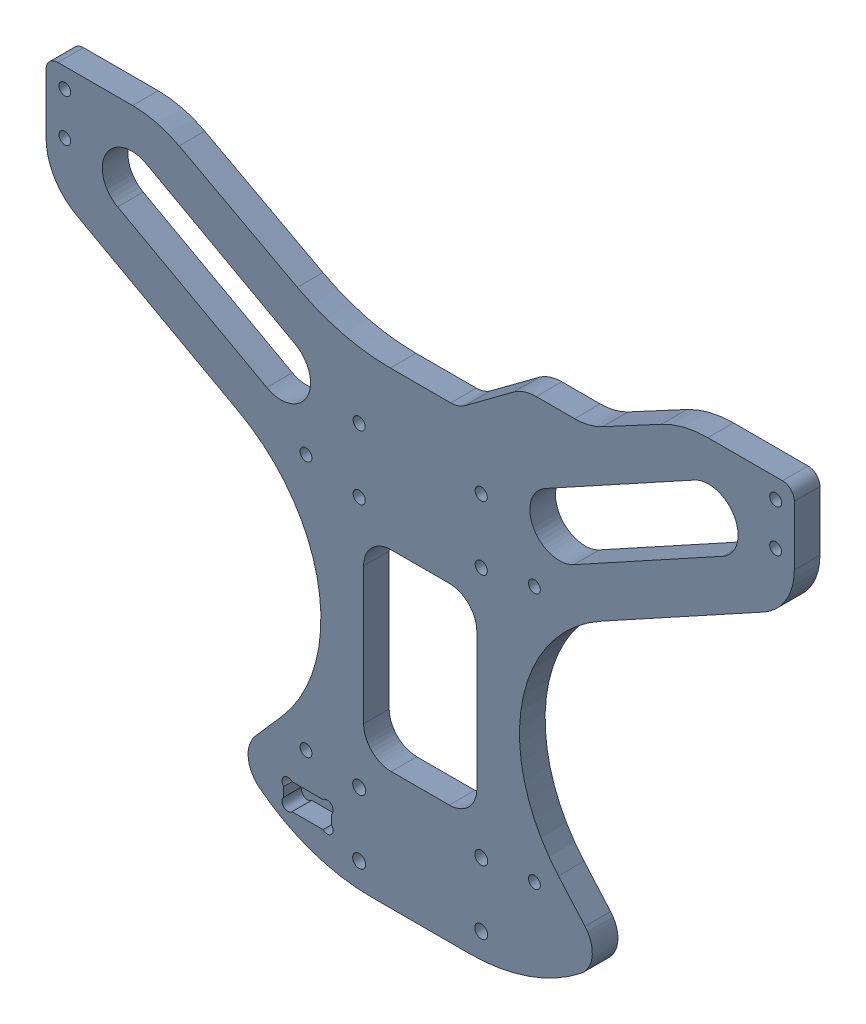
SolidWorks assembly MFG CW Base Plate Sub Asmbly, configuration Default. Lengths in mm.
Overall size (380 287.5 13).
13 component instances, 2 part files, 0 mates.
Components (placement in the parent):
- MFG CW Base Plate-1: MFG CW Base Plate [Default] at origin size (380 287.5 13)
- M6 x 1 Hex Nut-1: M6 x 1 Hex Nut [Default] at (-31 12.8 4.5) size (10 11.55 5)
- M6 x 1 Hex Nut-2: M6 x 1 Hex Nut [Default] at (-31 45.2 4.5) size (10 11.55 5)
- M6 x 1 Hex Nut-3: M6 x 1 Hex Nut [Default] at (31 12.8 4.5) size (10 11.55 5)
- M6 x 1 Hex Nut-4: M6 x 1 Hex Nut [Default] at (31 45.2 4.5) size (10 11.55 5)
- M6 x 1 Hex Nut-5: M6 x 1 Hex Nut [Default] at (-31 172.8 4.5) size (10 11.55 5)
- M6 x 1 Hex Nut-6: M6 x 1 Hex Nut [Default] at (-31 205.2 4.5) size (10 11.55 5)
- M6 x 1 Hex Nut-7: M6 x 1 Hex Nut [Default] at (31 172.8 4.5) size (10 11.55 5)
- M6 x 1 Hex Nut-8: M6 x 1 Hex Nut [Default] at (31 205.2 4.5) size (10 11.55 5)
- M6 x 1 Hex Nut-9: M6 x 1 Hex Nut [Default] at (-180.5 256 4.5) size (10 11.55 5)
- M6 x 1 Hex Nut-10: M6 x 1 Hex Nut [Default] at (-180.5 277.5 4.5) size (10 11.55 5)
- M6 x 1 Hex Nut-11: M6 x 1 Hex Nut [Default] at (180.5 256 4.5) size (10 11.55 5)
- M6 x 1 Hex Nut-12: M6 x 1 Hex Nut [Default] at (180.5 277.5 4.5) size (10 11.55 5)
